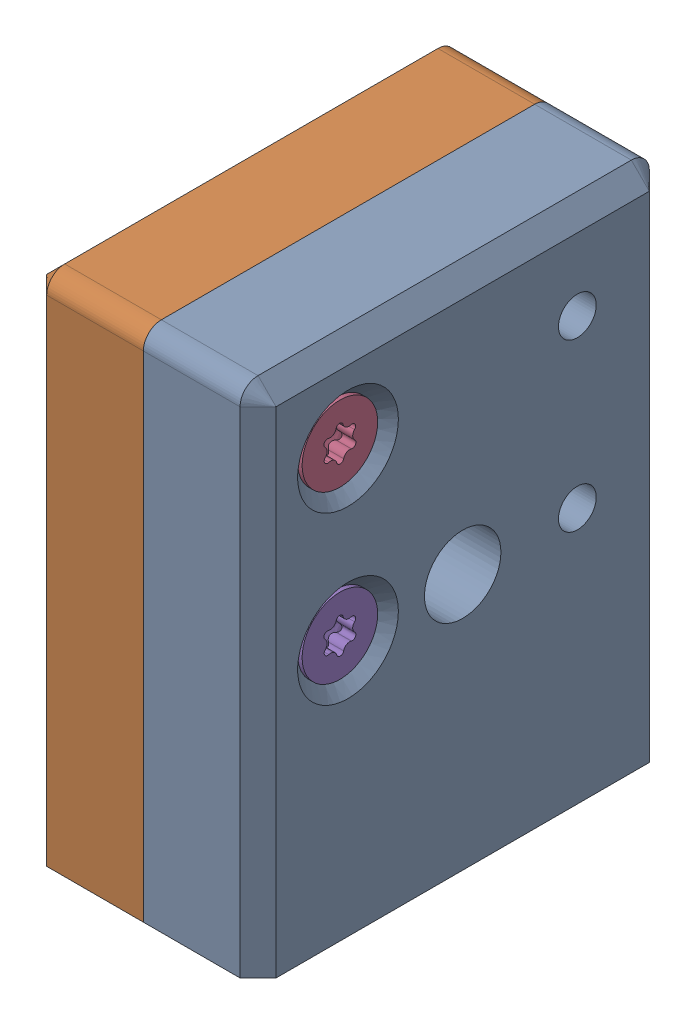
SolidWorks assembly TR23-RC-0200, configuration Default. Lengths in mm.
Overall size (25.5 57 45.5).
6 component instances, 2 part files, 0 mates.
Components (placement in the parent):
- TR23-RC-0030-1: TR23-RC-0030 [Default] at origin size (12.75 57 45.5)
- TR23-RC-0030-2: TR23-RC-0030 [Default] x (-1 0 0) z (0 0 -1) size (12.75 57 45.5)
- hexa csunk flathd screw_iso-1: hexa csunk flathd screw_iso [Default] at (-11.85 0 -12.75) x (0 -0.015611 0.999878) z (-1 0 0) size (8.4 8.4 12)
- hexa csunk flathd screw_iso-2: hexa csunk flathd screw_iso [Default] at (11.85 18.5 12.75) x (0 0.020995 -0.99978) z (1 0 0) size (8.4 8.4 12)
- hexa csunk flathd screw_iso-3: hexa csunk flathd screw_iso [Default] at (11.85 0 12.75) x (0 0.018618 -0.999827) z (1 0 0) size (8.4 8.4 12)
- hexa csunk flathd screw_iso-4: hexa csunk flathd screw_iso [Default] at (-11.85 18.5 -12.75) x (0 0.007453 0.999972) z (-1 0 0) size (8.4 8.4 12)
